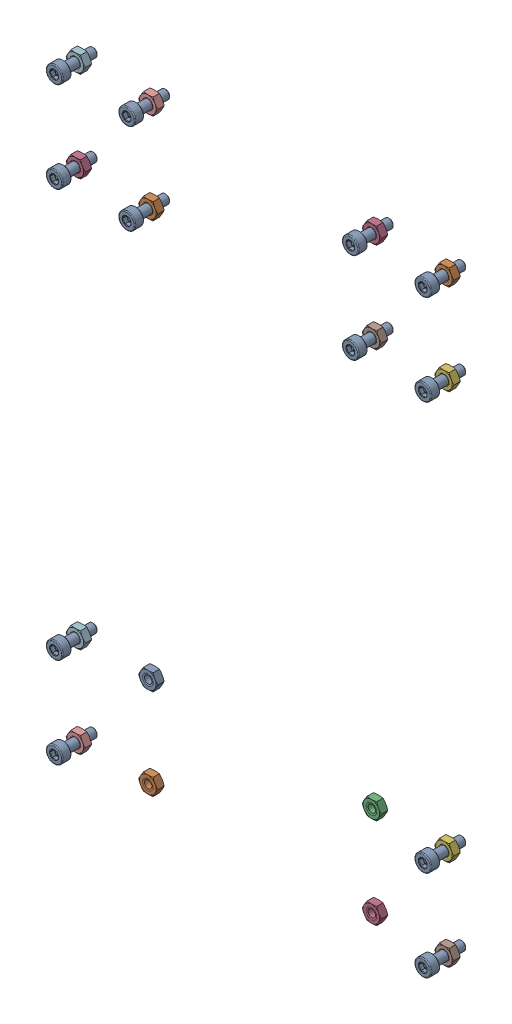
SolidWorks assembly Fasteners005-1, configuration Varsayılan. Lengths in mm.
Overall size (128.35 200.5 13.14).
40 component instances, 28 part files, 0 mates.
Components (placement in the parent):
- Screw and Nut M3x010_011-1-1: Screw and Nut M3x010_011-1 [Varsayılan] at (61 64.5 0) size (6.35 5.5 13.14)
  - M3x10-Screw010-1-1: M3x10-Screw010-1 [Varsayılan] at origin size (5.5 5.5 13.14)
  - M3-Nut042-1-1: M3-Nut042-1 [Varsayılan] at (0 0 -4) x (-1 0 0) z (0 0 -1) size (6.35 5.5 2.4)
- Screw and Nut M3x010_022-1-1: Screw and Nut M3x010_022-1 [Varsayılan] at (37 64.5 0) size (6.35 5.5 13.14)
  - M3x10-Screw021-1-1: M3x10-Screw021-1 [Varsayılan] at origin size (5.5 5.5 13.14)
  - M3-Nut053-1-1: M3-Nut053-1 [Varsayılan] at (0 0 -4) x (-1 0 0) z (0 0 -1) size (6.35 5.5 2.4)
- Screw and Nut M3x010_021-1-1: Screw and Nut M3x010_021-1 [Varsayılan] at (61 34.5 0) size (6.35 5.5 13.14)
  - M3x10-Screw020-1-1: M3x10-Screw020-1 [Varsayılan] at origin size (5.5 5.5 13.14)
  - M3-Nut052-1-1: M3-Nut052-1 [Varsayılan] at (0 0 -4) x (-1 0 0) z (0 0 -1) size (6.35 5.5 2.4)
- Screw and Nut M3x010_020-1-1: Screw and Nut M3x010_020-1 [Varsayılan] at (37 34.5 0) size (6.35 5.5 13.14)
  - M3x10-Screw019-1-1: M3x10-Screw019-1 [Varsayılan] at origin size (5.5 5.5 13.14)
  - M3-Nut051-1-1: M3-Nut051-1 [Varsayılan] at (0 0 -4) x (-1 0 0) z (0 0 -1) size (6.35 5.5 2.4)
- Screw and Nut M3x010_019-1-1: Screw and Nut M3x010_019-1 [Varsayılan] at (-37 64.5 0) size (6.35 5.5 13.14)
  - M3x10-Screw018-1-1: M3x10-Screw018-1 [Varsayılan] at origin size (5.5 5.5 13.14)
  - M3-Nut050-1-1: M3-Nut050-1 [Varsayılan] at (0 0 -4) x (-1 0 0) z (0 0 -1) size (6.35 5.5 2.4)
- Screw and Nut M3x010_018-1-1: Screw and Nut M3x010_018-1 [Varsayılan] at (-61 64.5 0) size (6.35 5.5 13.14)
  - M3x10-Screw017-1-1: M3x10-Screw017-1 [Varsayılan] at origin size (5.5 5.5 13.14)
  - M3-Nut049-1-1: M3-Nut049-1 [Varsayılan] at (0 0 -4) x (-1 0 0) z (0 0 -1) size (6.35 5.5 2.4)
- Screw and Nut M3x010_017-1-1: Screw and Nut M3x010_017-1 [Varsayılan] at (-37 34.5 0) size (6.35 5.5 13.14)
  - M3x10-Screw016-1-1: M3x10-Screw016-1 [Varsayılan] at origin size (5.5 5.5 13.14)
  - M3-Nut048-1-1: M3-Nut048-1 [Varsayılan] at (0 0 -4) x (-1 0 0) z (0 0 -1) size (6.35 5.5 2.4)
- Screw and Nut M3x010_016-1-1: Screw and Nut M3x010_016-1 [Varsayılan] at (-61 34.5 0) size (6.35 5.5 13.14)
  - M3x10-Screw015-1-1: M3x10-Screw015-1 [Varsayılan] at origin size (5.5 5.5 13.14)
  - M3-Nut047-1-1: M3-Nut047-1 [Varsayılan] at (0 0 -4) x (-1 0 0) z (0 0 -1) size (6.35 5.5 2.4)
- Screw and Nut M3x010_015-1-1: Screw and Nut M3x010_015-1 [Varsayılan] at (61 -100.5 0) size (6.35 5.5 13.14)
  - M3x10-Screw014-1-1: M3x10-Screw014-1 [Varsayılan] at origin size (5.5 5.5 13.14)
  - M3-Nut046-1-1: M3-Nut046-1 [Varsayılan] at (0 0 -4) x (-1 0 0) z (0 0 -1) size (6.35 5.5 2.4)
- Screw and Nut M3x010_014-1-1: Screw and Nut M3x010_014-1 [Varsayılan] at (61 -130.5 0) size (6.35 5.5 13.14)
  - M3x10-Screw013-1-1: M3x10-Screw013-1 [Varsayılan] at origin size (5.5 5.5 13.14)
  - M3-Nut045-1-1: M3-Nut045-1 [Varsayılan] at (0 0 -4) x (-1 0 0) z (0 0 -1) size (6.35 5.5 2.4)
- Screw and Nut M3x010_013-1-1: Screw and Nut M3x010_013-1 [Varsayılan] at (-61 -130.5 0) size (6.35 5.5 13.14)
  - M3x10-Screw012-1-1: M3x10-Screw012-1 [Varsayılan] at origin size (5.5 5.5 13.14)
  - M3-Nut044-1-1: M3-Nut044-1 [Varsayılan] at (0 0 -4) x (-1 0 0) z (0 0 -1) size (6.35 5.5 2.4)
- Screw and Nut M3x010_012-1-1: Screw and Nut M3x010_012-1 [Varsayılan] at (-61 -100.5 0) size (6.35 5.5 13.14)
  - M3x10-Screw011-1-1: M3x10-Screw011-1 [Varsayılan] at origin size (5.5 5.5 13.14)
  - M3-Nut043-1-1: M3-Nut043-1 [Varsayılan] at (0 0 -4) x (-1 0 0) z (0 0 -1) size (6.35 5.5 2.4)
- M3-Nut058-1-1: M3-Nut058-1 [Varsayılan] at (-37 -100.5 -4) x (-1 0 0) z (0 0 -1) size (6.35 5.5 2.4)
- M3-Nut059-1-1: M3-Nut059-1 [Varsayılan] at (-37 -130.5 -4) x (-1 0 0) z (0 0 -1) size (6.35 5.5 2.4)
- M3-Nut060-1-1: M3-Nut060-1 [Varsayılan] at (37 -100.5 -4) x (-1 0 0) z (0 0 -1) size (6.35 5.5 2.4)
- M3-Nut066-1-1: M3-Nut066-1 [Varsayılan] at (37 -130.5 -4) x (-1 0 0) z (0 0 -1) size (6.35 5.5 2.4)
